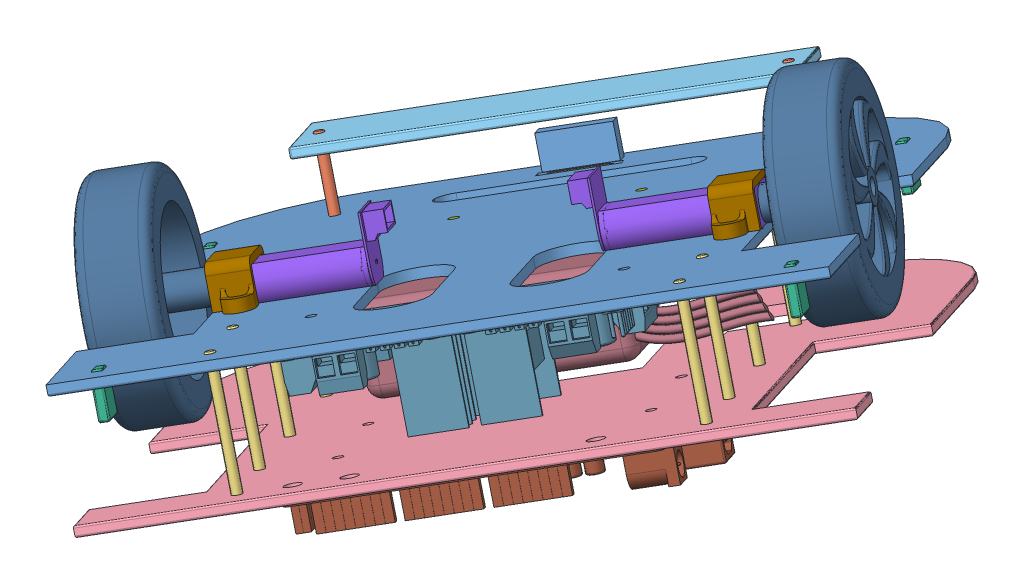
SolidWorks assembly body, configuration Default. Lengths in mm.
Overall size (276.36 186.92 286.97).
52 component instances, 16 part files, 40 mates.
Components (placement in the parent):
- Bottom-1: Bottom [Default] at (240.0196 -450.3378 91.3935) x (-0.748912 -0.245301 0.615596) z (0.507001 0.38608 0.770644) size (200 13 200)
- IR spacer-1: IR spacer [Default] at (237.7549 -445.4568 -6.8831) x (0.522625 0.093767 -0.847391) z (-0.738094 -0.447703 -0.504756) size (3 25 3)
- IR spacer-3: IR spacer [Default] at (147.8855 -474.893 66.9884) x (-0.879415 -0.365462 0.305068) z (0.211065 0.275078 0.937968) size (3 25 3)
- spacer-1: spacer [Default] at (180.6754 -475.4215 106.6688) x (-0.764646 -0.452027 -0.459335) z (-0.482946 -0.07001 0.872847) size (3 40 3)
- spacer-2: spacer [Default] at (222.0799 -492.4598 150.2506) x (0.374411 0.339543 0.86286) z (-0.823247 -0.306498 0.477832) size (3 40 3)
- spacer-3: spacer [Default] at (257.57 -465.4342 204.1957) x (0.903913 0.413434 -0.109611) z (0.029349 0.195711 0.980222) size (3 40 3)
- spacer-4: spacer [Default] at (242.3599 -477.0166 181.0764) x (0.903814 0.412806 -0.112741) z (0.032236 0.19703 0.979867) size (3 40 3)
- spacer-5: spacer [Default] at (332.2294 -447.5805 107.2049) x (-0.365654 -0.003 0.930746) z (-0.827174 -0.457407 -0.326439) size (3 40 3)
- spacer-6: spacer [Default] at (311.9493 -463.0237 76.3791) x (0.625269 0.42171 0.656658) z (-0.65342 -0.177175 0.735969) size (3 40 3)
- spacer-7: spacer [Default] at (270.5449 -445.9854 32.7973) x (-0.164362 -0.255408 -0.95276) z (-0.889328 -0.379469 0.255144) size (3 40 3)
- spacer-8: spacer [Default] at (347.4394 -435.9981 130.3242) x (-0.36301 -0.001539 0.931784) z (-0.828337 -0.457414 -0.323464) size (3 40 3)
- top final-1: top final [Default] at (255.3811 -482.3509 97.3253) x (-0.748912 -0.245301 0.615596) z (0.507001 0.38608 0.770644) size (200 13 200)
- IR panel-1: IR panel [Default] at (194.3137 -463.2873 30.6293) x (0.748912 0.245301 -0.615596) z (0.507001 0.38608 0.770644) size (130 3 30)
- t sensor-1: t sensor [Default] at (148.2719 -499.2141 101.6269) x (-0.507001 -0.38608 -0.770644) z (-0.426709 0.889252 -0.164772) size (10 3 13)
- t sensor-2: t sensor [Default] at (220.5544 -443.1963 216.7584) x (0.507001 0.38608 0.770644) z (-0.426709 0.889252 -0.164772) size (10 3 13)
- t sensor-3: t sensor [Default] at (355.3585 -399.0421 105.9511) x (-0.507001 -0.38608 -0.770644) z (-0.426709 0.889252 -0.164772) size (10 3 13)
- t sensor-4: t sensor [Default] at (278.5826 -456.5317 -5.4867) x (0.507001 0.38608 0.770644) z (-0.426709 0.889252 -0.164772) size (10 3 13)
- 6mm spacer-1: 6mm spacer [Default] at (201.415 -479.2204 71.9061) x (0.904194 0.42326 -0.057306) z (-0.018782 0.173438 0.984666) size (3 6 3)
- 6mm spacer-6: 6mm spacer [Default] at (237.3627 -467.446 42.3575) x (0.897667 0.394277 -0.196822) z (0.110059 0.231896 0.966494) size (3 6 3)
- wheel motor assembly-4: wheel motor assembly [Default] at (224.715 -474.8179 183.2493) x (0.748912 0.245301 -0.615596) z (-0.426709 0.889252 -0.164772) size (75.28 65 65)
  - micro motor assembly-1: micro motor assembly [Default] at (55.842 39.7821 20.1236) x (0 -1 0) z (-1 0 0) size (14.6 19.3 56.48)
    - Part1-1: Part1 [Default] at (12.3025 15.25 27.8292) size (14.6 19.3 56.48)
  - Part2_1-1: Part2_1 [Default] at (9.7628 27.4795 30.0736) x (0 -1 0) z (-1 0 0) size (29.6 12.6 11.51)
  - wheel1-1: wheel1 [Default] at (-23.9872 27.4795 35.3736) x (0 -1 0) z (0 0 1) size (65 28.8 65)
- wheel motor assembly-5: wheel motor assembly [Default] at (307.7088 -459.7256 49.7715) x (-0.748912 -0.245301 0.615596) z (-0.426709 0.889252 -0.164772) size (75.28 65 65)
  - micro motor assembly-1: micro motor assembly [Default] at (55.842 39.7821 20.1236) x (0 -1 0) z (-1 0 0) size (14.6 19.3 56.48)
    - Part1-1: Part1 [Default] at (12.3025 15.25 27.8292) size (14.6 19.3 56.48)
  - Part2_1-1: Part2_1 [Default] at (9.7628 27.4795 30.0736) x (0 -1 0) z (-1 0 0) size (29.6 12.6 11.51)
  - wheel1-1: wheel1 [Default] at (-23.9872 27.4795 35.3736) x (0 -1 0) z (0 0 1) size (65 28.8 65)
- ARDUINO MEGA-1: ARDUINO MEGA [Default] at (293.8708 -457.8048 148.3281) x (-0.748912 -0.245301 0.615596) z (0.507001 0.38608 0.770644) size (108 12.8 52)
- tcs34725-1: tcs34725 [Default] at (200.1491 -492.8286 26.0185) x (-0.748912 -0.245301 0.615596) z (0.426709 -0.889252 0.164772) size (20.3 2.67 20)
- batt-1: batt [Default] at (270.664 -428.9031 145.9212) x (0.507001 0.38608 0.770644) z (0.748912 0.245301 -0.615596) size (58.61 25 130.11)
- L298N Stepper Motor Driver Assembly-1: L298N Stepper Motor Driver Assembly [Default] at (255.5695 -426.9058 134.486) x (0.507001 0.38608 0.770644) z (0.748912 0.245301 -0.615596) size (43 28.01 43)
  - L298N Stepper Motor Driver (Red)-Part File-1: L298N Stepper Motor Driver (Red)-Part File [Default] at (16.8606 10.1012 32.1341) size (43 28.01 43)
  - pan head cross recess screw_iso_ISO 7045 - M1.6 x 4 - Z - 4N-1: pan head cross recess screw_iso_ISO 7045 - M1.6 x 4 - Z - 4N [Default] at (-1.3394 22.4012 35.9476) x (0 -1 0) z (-0.742963 0 0.669332) size (5.3 3.2 3.23)
  - pan head cross recess screw_iso_ISO 7045 - M1.6 x 4 - Z - 4N-2: pan head cross recess screw_iso_ISO 7045 - M1.6 x 4 - Z - 4N [Default] at (-1.3394 22.4012 41.5921) x (0 -1 0) z (-0.751552 0 0.659674) size (5.3 3.2 3.23)
  - pan head cross recess screw_iso_ISO 7045 - M1.6 x 4 - Z - 4N-3: pan head cross recess screw_iso_ISO 7045 - M1.6 x 4 - Z - 4N [Default] at (3.7852 22.4012 50.3107) x (0 -1 0) z (0.734198 0 -0.678936) size (5.3 3.2 3.23)
  - pan head cross recess screw_iso_ISO 7045 - M1.6 x 4 - Z - 4N-4: pan head cross recess screw_iso_ISO 7045 - M1.6 x 4 - Z - 4N [Default] at (14.2688 22.4012 50.3107) x (0 -1 0) z (0.720108 0 0.693862) size (5.3 3.2 3.23)
  - pan head cross recess screw_iso_ISO 7045 - M1.6 x 4 - Z - 4N-5: pan head cross recess screw_iso_ISO 7045 - M1.6 x 4 - Z - 4N [Default] at (9.027 22.4012 50.3107) x (0 -1 0) z (0.308372 0 0.951266) size (5.3 3.2 3.23)
  - pan head cross recess screw_iso_ISO 7045 - M1.6 x 4 - Z - 4N-6: pan head cross recess screw_iso_ISO 7045 - M1.6 x 4 - Z - 4N [Default] at (33.6606 22.4012 35.9476) x (0 -1 0) z (0 0 1) size (5.3 3.2 3.23)
  - pan head cross recess screw_iso_ISO 7045 - M1.6 x 4 - Z - 4N-7: pan head cross recess screw_iso_ISO 7045 - M1.6 x 4 - Z - 4N [Default] at (33.6606 22.4012 41.6421) x (0 -1 0) z (-0.222944 0 0.974831) size (5.3 3.2 3.23)
  - countersunk flat head cross recess screw_iso_ISO 7046-1 - M2.5 x 3 - Z - 3N-1: countersunk flat head cross recess screw_iso_ISO 7046-1 - M2.5 x 3 - Z - 3N [Default] at (16.3567 30.6012 21.6857) x (0 0 -1) z (1 0 0) size (3 4.7 4.7)
- L298N Stepper Motor Driver Assembly-2: L298N Stepper Motor Driver Assembly [Default] at (286.3475 -409.4056 149.2271) x (-0.507001 -0.38608 -0.770644) z (-0.748912 -0.245301 0.615596) size (43 28.01 43)
  - L298N Stepper Motor Driver (Red)-Part File-1: L298N Stepper Motor Driver (Red)-Part File [Default] at (16.8606 10.1012 32.1341) size (43 28.01 43)
  - pan head cross recess screw_iso_ISO 7045 - M1.6 x 4 - Z - 4N-1: pan head cross recess screw_iso_ISO 7045 - M1.6 x 4 - Z - 4N [Default] at (-1.3394 22.4012 35.9476) x (0 -1 0) z (-0.742963 0 0.669332) size (5.3 3.2 3.23)
  - pan head cross recess screw_iso_ISO 7045 - M1.6 x 4 - Z - 4N-2: pan head cross recess screw_iso_ISO 7045 - M1.6 x 4 - Z - 4N [Default] at (-1.3394 22.4012 41.5921) x (0 -1 0) z (-0.751552 0 0.659674) size (5.3 3.2 3.23)
  - pan head cross recess screw_iso_ISO 7045 - M1.6 x 4 - Z - 4N-3: pan head cross recess screw_iso_ISO 7045 - M1.6 x 4 - Z - 4N [Default] at (3.7852 22.4012 50.3107) x (0 -1 0) z (0.734198 0 -0.678936) size (5.3 3.2 3.23)
  - pan head cross recess screw_iso_ISO 7045 - M1.6 x 4 - Z - 4N-4: pan head cross recess screw_iso_ISO 7045 - M1.6 x 4 - Z - 4N [Default] at (14.2688 22.4012 50.3107) x (0 -1 0) z (0.720108 0 0.693862) size (5.3 3.2 3.23)
  - pan head cross recess screw_iso_ISO 7045 - M1.6 x 4 - Z - 4N-5: pan head cross recess screw_iso_ISO 7045 - M1.6 x 4 - Z - 4N [Default] at (9.027 22.4012 50.3107) x (0 -1 0) z (0.308372 0 0.951266) size (5.3 3.2 3.23)
  - pan head cross recess screw_iso_ISO 7045 - M1.6 x 4 - Z - 4N-6: pan head cross recess screw_iso_ISO 7045 - M1.6 x 4 - Z - 4N [Default] at (33.6606 22.4012 35.9476) x (0 -1 0) z (0 0 1) size (5.3 3.2 3.23)
  - pan head cross recess screw_iso_ISO 7045 - M1.6 x 4 - Z - 4N-7: pan head cross recess screw_iso_ISO 7045 - M1.6 x 4 - Z - 4N [Default] at (33.6606 22.4012 41.6421) x (0 -1 0) z (-0.222944 0 0.974831) size (5.3 3.2 3.23)
  - countersunk flat head cross recess screw_iso_ISO 7046-1 - M2.5 x 3 - Z - 3N-1: countersunk flat head cross recess screw_iso_ISO 7046-1 - M2.5 x 3 - Z - 3N [Default] at (16.3567 30.6012 21.6857) x (0 0 -1) z (1 0 0) size (3 4.7 4.7)
Mates (geometry in assembly coordinates):
- Coincident28: coincident anti-aligned: circle of Bottom-1; circle of IR spacer-1
- Concentric13: concentric aligned: cylinder of Bottom-1 through (180.8888 -475.8661 106.7512) axis (0.426709 -0.889252 0.164772) radius 1.5; circle of spacer-1
- Coincident71: coincident anti-aligned: plane of Bottom-1 through (240.0196 -450.3378 91.3935) normal (-0.426709 0.889252 -0.164772); circle of spacer-1
- Concentric14: concentric anti-aligned: cylinder of Bottom-1 through (205.2249 -457.3343 143.7421) axis (0.426709 -0.889252 0.164772) radius 1.5; circle of spacer-2
- Coincident73: coincident anti-aligned: plane of Bottom-1 through (240.0196 -450.3378 91.3935) normal (-0.426709 0.889252 -0.164772); circle of spacer-2
- Concentric15: concentric aligned: cylinder of Bottom-1 through (240.715 -430.3088 197.6872) axis (0.426709 -0.889252 0.164772) radius 1.5; cylinder of spacer-3 through (240.5016 -429.8641 197.6048) axis (0.426709 -0.889252 0.164772) radius 1.5
- Coincident74: coincident anti-aligned: plane of Bottom-1 through (240.0196 -450.3378 91.3935) normal (-0.426709 0.889252 -0.164772); circle of spacer-3
- Coincident75: coincident aligned: cylinder of Bottom-1 through (225.5049 -441.8911 174.5679) axis (0.426709 -0.889252 0.164772) radius 1.5; circle of spacer-4
- Coincident76: coincident anti-aligned: plane of Bottom-1 through (240.0196 -450.3378 91.3935) normal (-0.426709 0.889252 -0.164772); circle of spacer-4
- Coincident85: coincident anti-aligned: circle of IR spacer-3; plane of IR panel-1 through (193.0336 -460.6195 30.135) normal (-0.426709 0.889252 -0.164772)
- Concentric18: concentric anti-aligned: circle of IR spacer-1; circle of IR panel-1
- Concentric19: concentric anti-aligned: circle of spacer-3; cylinder of top final-1 through (256.0765 -462.3218 203.619) axis (0.426709 -0.889252 0.164772) radius 1.5
- Coincident87: coincident anti-aligned: circle of spacer-1; cylinder of top final-1 through (196.2503 -507.8792 112.683) axis (0.426709 -0.889252 0.164772) radius 1.5
- Coincident88: coincident anti-aligned: circle of spacer-3; plane of top final-1 through (256.6612 -485.0187 97.8196) normal (0.426709 -0.889252 0.164772)
- Parallel18: parallel aligned: plane of Bottom-1 through (217.1086 -438.9278 230.5118) normal (-0.748912 -0.245301 0.615596); plane of t sensor-1 through (146.0252 -499.95 103.4737) normal (-0.748912 -0.245301 0.615596)
- Coincident104: coincident anti-aligned: plane of Bottom-1 through (219.2616 -436.8956 217.6964) normal (0.748912 0.245301 -0.615596); plane of t sensor-2 through (220.5544 -443.1963 216.7584) normal (-0.748912 -0.245301 0.615596)
- Coincident105: coincident anti-aligned: plane of Bottom-1 through (218.9734 -438.0901 211.9964) normal (0.507001 0.38608 0.770644); plane of t sensor-2 through (216.5133 -438.3814 213.7608) normal (-0.507001 -0.38608 -0.770644)
- Coincident106: coincident: plane of Bottom-1 through (240.0196 -450.3378 91.3935) normal (-0.426709 0.889252 -0.164772); line of t sensor-2 through (219.0081 -437.0887 217.311) axis (-0.507001 -0.38608 -0.770644)
- Coincident113: coincident anti-aligned: plane of Bottom-1 through (144.7324 -493.6493 104.4117) normal (-0.507001 -0.38608 -0.770644); plane of t sensor-1 through (146.7658 -492.4688 102.4825) normal (0.507001 0.38608 0.770644)
- Coincident114: coincident anti-aligned: line of Bottom-1 through (142.1974 -495.5797 100.5585) axis (0.507001 0.38608 0.770644); line of t sensor-1 through (144.4789 -493.8424 104.0264) axis (-0.507001 -0.38608 -0.770644)
- Concentric20: concentric aligned: cylinder of Bottom-1 through (195.8677 -467.6601 69.7641) axis (0.426709 -0.889252 0.164772) radius 1.5; cylinder of 6mm spacer-1 through (198.8547 -473.8849 70.9175) axis (0.426709 -0.889252 0.164772) radius 1.5
- Coincident115: coincident aligned: plane of Bottom-1 through (240.0196 -450.3378 91.3935) normal (-0.426709 0.889252 -0.164772); plane of 6mm spacer-1 through (198.8547 -473.8849 70.9175) normal (-0.426709 0.889252 -0.164772)
- Concentric22: concentric aligned: cylinder of Bottom-1 through (231.8155 -455.8857 40.2155) axis (0.426709 -0.889252 0.164772) radius 1.5; cylinder of 6mm spacer-6 through (234.8025 -462.1104 41.3689) axis (0.426709 -0.889252 0.164772) radius 1.5
- Coincident117: coincident aligned: plane of Bottom-1 through (240.0196 -450.3378 91.3935) normal (-0.426709 0.889252 -0.164772); plane of 6mm spacer-6 through (234.8025 -462.1104 41.3689) normal (-0.426709 0.889252 -0.164772)
- Concentric26: concentric anti-aligned: cylinder of IR spacer-3 through (158.5532 -497.1243 71.1077) axis (-0.426709 0.889252 -0.164772) radius 1.5; cylinder of IR panel-1 through (148.0988 -475.3376 67.0708) axis (0.426709 -0.889252 0.164772) radius 1.5
- Coincident119: coincident anti-aligned: plane of Bottom-1 through (240.0196 -450.3378 91.3935) normal (-0.426709 0.889252 -0.164772); plane of wheel motor assembly-4/micro motor assembly-1/Part1-1 through (205.0326 -457.1558 145.2038) normal (0.426709 -0.889252 0.164772)
- Coincident127: coincident anti-aligned: plane of top final-1 through (256.6612 -485.0187 97.8196) normal (0.426709 -0.889252 0.164772); plane of ARDUINO MEGA-1 through (313.01 -457.8714 98.4036) normal (-0.426709 0.889252 -0.164772)
- Concentric27: concentric anti-aligned: cylinder of top final-1 through (321.108 -434.0381 145.3679) axis (0.426709 -0.889252 0.164772) radius 2.5; axis of ARDUINO MEGA-1 through (326.1431 -444.5313 147.3122) axis (-0.426709 0.889252 -0.164772)
- Parallel29: parallel aligned: plane of top final-1 through (208.5045 -511.0823 142.559) normal (-0.748912 -0.245301 0.615596); plane of ARDUINO MEGA-1 through (245.8596 -476.5069 171.7293) normal (-0.748912 -0.245301 0.615596)
- Coincident139: coincident anti-aligned: plane of Bottom-1 through (187.6724 -486.6251 31.119) normal (-0.507001 -0.38608 -0.770644); plane of tcs34725-1 through (191.2667 -488.0615 29.474) normal (0.507001 0.38608 0.770644)
- Coincident141: coincident aligned: plane of Bottom-1 through (240.0196 -450.3378 91.3935) normal (-0.426709 0.889252 -0.164772); plane of tcs34725-1 through (200.7442 -482.7068 18.4138) normal (-0.426709 0.889252 -0.164772)
- Distance7: distance = 1 mm: line of Bottom-1 through (203.9076 -485.0545 15.7583) axis (0.507001 0.38608 0.770644); line of tcs34725-1 through (203.7303 -484.3424 17.2687) axis (0.507001 0.38608 0.770644)
- Coincident142: coincident aligned: plane of Bottom-1 through (188.0729 -482.93 128.9208) normal (-0.748912 -0.245301 0.615596); plane of wheel motor assembly-4/Part2_1-1 through (199.901 -446.8465 157.6889) normal (-0.748912 -0.245301 0.615596)
- Distance9: distance = 67 mm: line of Bottom-1 through (365.6109 -387.1998 106.8983) axis (-0.748912 -0.245301 0.615596); cylinder of wheel motor assembly-4/micro motor assembly-1/Part1-1 through (205.4341 -450.7791 148.2332) axis (0.748912 0.245301 -0.615596) radius 7.0711
- Coincident144: coincident anti-aligned: plane of Bottom-1 through (241.2997 -453.0056 91.8878) normal (0.426709 -0.889252 0.164772); plane of batt-1 through (270.664 -428.9031 145.9212) normal (-0.426709 0.889252 -0.164772)
- Parallel34: parallel aligned: plane of Bottom-1 through (115.7083 -516.1437 76.383) normal (-0.507001 -0.38608 -0.770644); plane of batt-1 through (225.7498 -483.5957 118.7916) normal (-0.507001 -0.38608 -0.770644)
- Distance10: distance = 34 mm: line of Bottom-1 through (219.9239 -446.6962 181.2957) axis (-0.507001 -0.38608 -0.770644); cylinder of batt-1 through (219.7846 -463.9402 112.869) axis (-0.507001 -0.38608 -0.770644) radius 4
- Coincident146: coincident: plane of Bottom-1 through (241.2997 -453.0056 91.8878) normal (0.426709 -0.889252 0.164772); plane of L298N Stepper Motor Driver Assembly-1/L298N Stepper Motor Driver (Red)-Part File-1 through (289.0678 -424.1052 124.1548) normal (-0.426709 0.889252 -0.164772)
- Distance11: distance = 55 mm: line of L298N Stepper Motor Driver Assembly-1/L298N Stepper Motor Driver (Red)-Part File-1 through (297.6948 -424.5231 99.5581) axis (0.507001 0.38608 0.770644); line of Bottom-1 through (346.49 -405.2403 77.26) axis (0.507001 0.38608 0.770644)
- Distance12: distance = 11 mm: line of L298N Stepper Motor Driver Assembly-1/L298N Stepper Motor Driver (Red)-Part File-1 through (319.4959 -407.9217 132.6958) axis (-0.748912 -0.245301 0.615596); line of Bottom-1 through (366.2631 -390.1832 107.3151) axis (-0.748912 -0.245301 0.615596)
